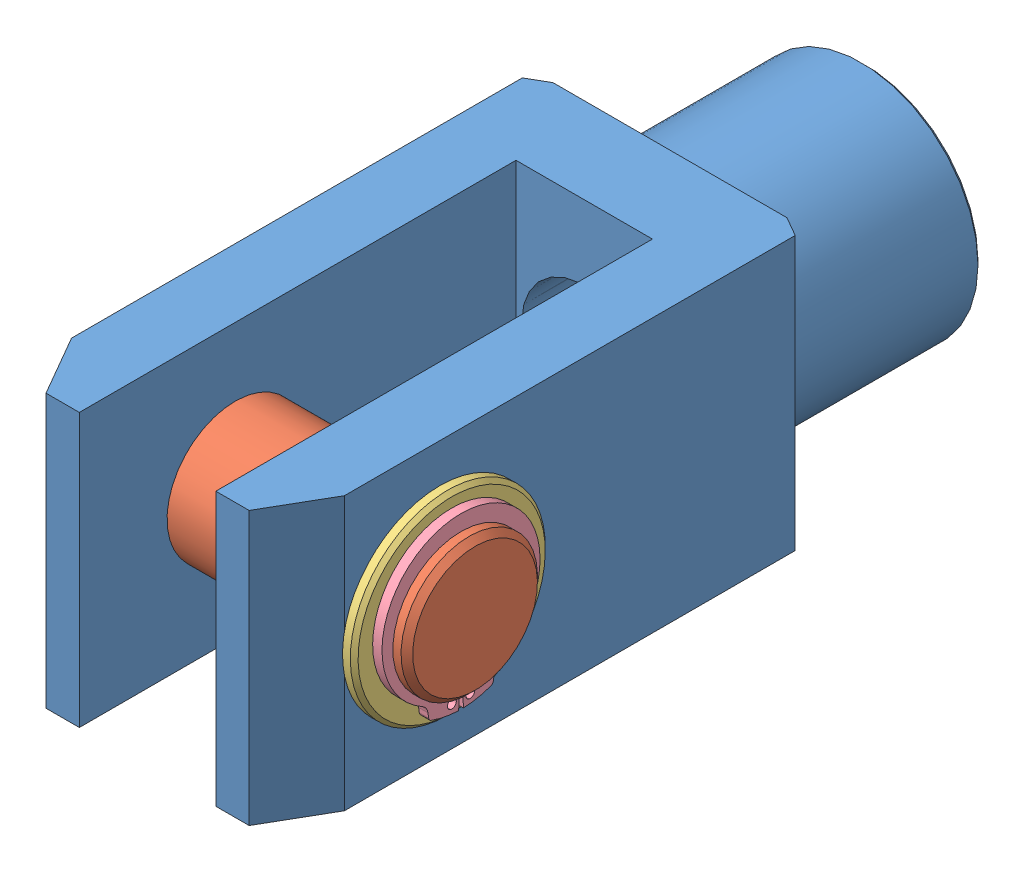
SolidWorks assembly Janatics-AF035, configuration Default. Lengths in mm.
Overall size (88 70 184).
6 component instances, 4 part files, 12 mates.
Components (placement in the parent):
- Janatics-AF035_010073 (Fork)-1: Janatics-AF035_010073 (Fork) [Default] at (24.2306 -22.651 -89.3974) size (70 70 184)
- Janatics-AF035_010074 (Fork pin)-2: Janatics-AF035_010074 (Fork pin) [Default] at (-19.7694 -22.651 54.6026) x (1 0 0) z (0 -0.579855 0.81472) size (88 35 35)
- Janatics-AF035_838032 (Washer)-1: Janatics-AF035_838032 (Washer) [Default] at (-10.7694 -47.651 54.6026) x (0 1 0) z (0 0 1) size (50 3 50)
- Janatics-AF035_838032 (Washer)-3: Janatics-AF035_838032 (Washer) [Default] at (59.2306 2.349 54.6026) x (0 -1 0) z (0 0 1) size (50 3 50)
- Janatics-AF035_heavy duty external retaining ring_am-1: Janatics-AF035_heavy duty external retaining ring_am [B27.8M - 3DM1-35] at (62.2306 -22.651 54.6026) x (0 0 1) z (-1 0 0) size (40.54 43.49 2.4)
- Janatics-AF035_heavy duty external retaining ring_am-2: Janatics-AF035_heavy duty external retaining ring_am [B27.8M - 3DM1-35] at (-13.7694 -23.8827 54.6026) x (0 0 -1) z (1 0 0) size (40.54 43.49 2.4)
Mates (geometry in assembly coordinates):
- Concentric4: concentric: circle of Janatics-AF035_010073 (Fork)-1; circle of Janatics-AF035_010074 (Fork pin)-2
- Distance1: distance = 9 mm: plane of Janatics-AF035_010073 (Fork)-1 through (-10.7694 12.349 94.6026) normal (-1 0 0); plane of Janatics-AF035_010074 (Fork pin)-2 through (-19.7694 -22.651 54.6026) normal (-1 0 0)
- Concentric6: concentric: circle of Janatics-AF035_010073 (Fork)-1; circle of Janatics-AF035_838032 (Washer)-1
- Coincident4: coincident: plane of Janatics-AF035_010073 (Fork)-1 through (-10.7694 12.349 94.6026) normal (-1 0 0); plane of Janatics-AF035_838032 (Washer)-1 through (-10.7694 -47.651 54.6026) normal (1 0 0)
- Concentric7: concentric: circle of Janatics-AF035_010073 (Fork)-1; circle of Janatics-AF035_838032 (Washer)-3
- Coincident5: coincident: plane of Janatics-AF035_010073 (Fork)-1 through (59.2306 12.349 94.6026) normal (1 0 0); plane of Janatics-AF035_838032 (Washer)-3 through (59.2306 2.349 54.6026) normal (-1 0 0)
- Concentric8: concentric: circle of Janatics-AF035_010074 (Fork pin)-2; circle of Janatics-AF035_heavy duty external retaining ring_am-1
- Concentric9: concentric: cylinder of Janatics-AF035_010074 (Fork pin)-2 through (-21.7694 -22.651 54.6026) axis (-1 0 0) radius 16.5; cylinder of Janatics-AF035_heavy duty external retaining ring_am-1 through (64.6306 -22.651 54.6026) axis (-1 0 0) radius 16.4
- Coincident12: coincident: plane of Janatics-AF035_838032 (Washer)-3 through (62.2306 2.349 54.6026) normal (1 0 0); plane of Janatics-AF035_heavy duty external retaining ring_am-1 through (62.2306 -22.651 54.6026) normal (-1 0 0)
- Coincident13: coincident: circle of Janatics-AF035_010074 (Fork pin)-2; plane of Janatics-AF035_heavy duty external retaining ring_am-2 through (-13.7694 -23.8827 54.6026) normal (1 0 0)
- Concentric15: concentric: cylinder of Janatics-AF035_010074 (Fork pin)-2 through (-21.7694 -22.651 54.6026) axis (-1 0 0) radius 17.5; circle of Janatics-AF035_heavy duty external retaining ring_am-2
- Concentric16: concentric: cylinder of Janatics-AF035_010073 (Fork)-1 through (-10.7694 -22.651 54.6026) axis (1 0 0) radius 17.5; cylinder of Janatics-AF035_010074 (Fork pin)-2 through (-21.7694 -22.651 54.6026) axis (-1 0 0) radius 17.5
